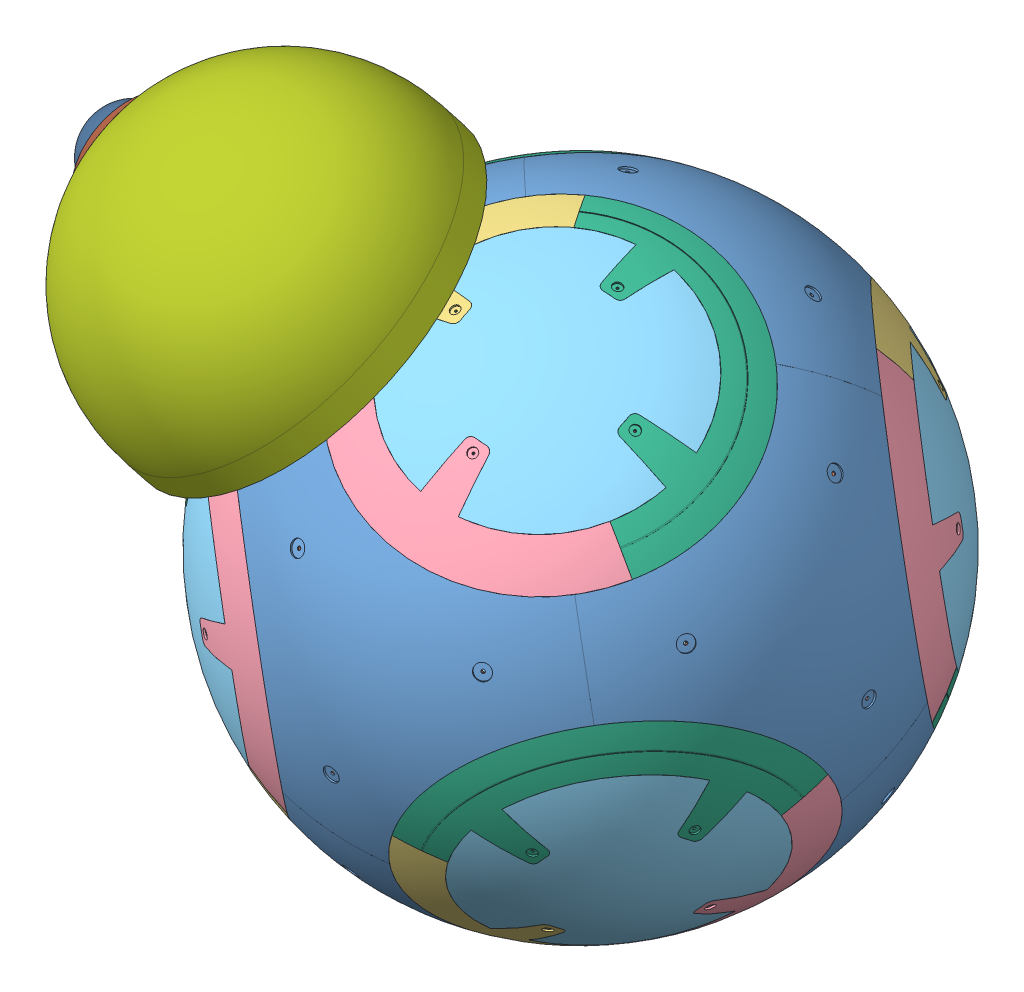
SolidWorks assembly BB-8, configuration Default. Lengths in mm.
Overall size (733.51 768.7 748.54).
63 component instances, 12 part files, 67 mates.
Components (placement in the parent):
- BB-8Shell2-41: BB-8Shell2 [Default] at (-357.0891 -1245.3708 1823.2299) x (-0.707206 0.437014 -0.555769) z (-0.249951 -0.889864 -0.381663) size (215.21 215.21 215.21)
- BB-8Shell2-42: BB-8Shell2 [Default] at (-357.0891 -1245.3708 1823.2299) x (-0.249951 -0.889864 -0.381663) z (-0.661351 -0.131 0.738549) size (215.21 215.21 215.21)
- BB-8Shell2-43: BB-8Shell2 [Default] at (-357.0891 -1245.3708 1823.2299) x (-0.707206 0.437014 -0.555769) z (0.661351 0.131 -0.738549) size (215.21 215.21 215.21)
- BB-8Shell2-44: BB-8Shell2 [Default] at (-357.0891 -1245.3708 1823.2299) x (-0.707206 0.437014 -0.555769) z (-0.661351 -0.131 0.738549) size (215.21 215.21 215.21)
- BB-8Shell2-45: BB-8Shell2 [Default] at (-357.0891 -1245.3708 1823.2299) x (0.661351 0.131 -0.738549) z (-0.707206 0.437014 -0.555769) size (215.21 215.21 215.21)
- BB-8Shell2-46: BB-8Shell2 [Default] at (-357.0891 -1245.3708 1823.2299) x (-0.249951 -0.889864 -0.381663) z (-0.707206 0.437014 -0.555769) size (215.21 215.21 215.21)
- BB-8Shell2-47: BB-8Shell2 [Default] at (-357.0891 -1245.3708 1823.2299) x (0.707206 -0.437014 0.555769) z (0.661351 0.131 -0.738549) size (215.21 215.21 215.21)
- BB-8Shell2-48: BB-8Shell2 [Default] at (-357.0891 -1245.3708 1823.2299) x (0.707206 -0.437014 0.555769) z (0.249951 0.889864 0.381663) size (215.21 215.21 215.21)
- BB-8Shell3-2: BB-8Shell3 [Default] at (-357.0891 -1245.3708 1823.2299) x (-0.644387 -0.72186 0.252356) z (0.707206 -0.437014 0.555769) size (40 18.04 169.3)
- BB-8Shell3-3: BB-8Shell3 [Default] at (-357.0891 -1245.3708 1823.2299) x (0.323328 -0.938244 0.123111) z (-0.661351 -0.131 0.738549) size (40 18.04 169.3)
- BB-8Shell3-4: BB-8Shell3 [Default] at (-357.0891 -1245.3708 1823.2299) x (0.290904 -0.536598 -0.792109) z (-0.707206 0.437014 -0.555769) size (40 18.04 169.3)
- BB-8Shell3-7: BB-8Shell3 [Default] at (-357.0891 -1245.3708 1823.2299) x (-0.967716 0.216385 0.129245) z (0.249951 0.889864 0.381663) size (40 18.04 169.3)
- BB-8Shell3-10: BB-8Shell3 [Default] at (-357.0891 -1245.3708 1823.2299) x (-0.644387 -0.72186 0.252356) z (-0.707206 0.437014 -0.555769) size (40 18.04 169.3)
- BB-8Shell3-11: BB-8Shell3 [Default] at (-357.0891 -1245.3708 1823.2299) x (0.290904 -0.536598 -0.792109) z (0.707206 -0.437014 0.555769) size (40 18.04 169.3)
- BB-8Shell3-13: BB-8Shell3 [Default] at (-357.0891 -1245.3708 1823.2299) x (0.967716 -0.216385 -0.129245) z (0.249951 0.889864 0.381663) size (40 18.04 169.3)
- BB-8Shell3-14: BB-8Shell3 [Default] at (-357.0891 -1245.3708 1823.2299) x (0.323328 -0.938244 0.123111) z (0.661351 0.131 -0.738549) size (40 18.04 169.3)
- BB-8Shell3-15: BB-8Shell3 [Default] at (-357.0891 -1245.3708 1823.2299) x (-0.676812 -0.320213 -0.662864) z (0.661351 0.131 -0.738549) size (40 18.04 169.3)
- BB-8Shell3-16: BB-8Shell3 [Default] at (-357.0891 -1245.3708 1823.2299) x (-0.676812 -0.320213 -0.662864) z (-0.661351 -0.131 0.738549) size (40 18.04 169.3)
- BB-8Shell3-17: BB-8Shell3 [Default] at (-357.0891 -1245.3708 1823.2299) x (0.032424 -0.401646 0.915221) z (-0.249951 -0.889864 -0.381663) size (40 18.04 169.3)
- BB-8Shell3-18: BB-8Shell3 [Default] at (-357.0891 -1245.3708 1823.2299) x (-0.032424 0.401646 -0.915221) z (-0.249951 -0.889864 -0.381663) size (40 18.04 169.3)
- BB-8Panel-1: BB-8Panel [Default] at (-341.2732 -1423.0162 1729.0677) x (0.967716 -0.216385 -0.129245) z (0.032424 -0.401646 0.915221) size (286.79 46.44 286.79)
  - BB-8Shell4-2: BB-8Shell4 [Default] at (-65.915 190.0653 14.3158) size (89.69 38.2 195.88)
  - BB-8Shell5-2: BB-8Shell5 [Default] at (-65.915 190.0653 14.3158) x (0 0 -1) z (1 0 0) size (89.69 38.2 248.37)
  - BB-8Shell6-4: BB-8Shell6 [Default] at (-65.915 190.0653 14.3158) size (217.05 29.8 217.05)
  - BB-8Shell1-2: BB-8Shell1 [Default] at (-65.915 190.0653 14.3158) x (0 0 1) z (-1 0 0) size (215.09 38.2 215.09)
- BB-8Panel-2: BB-8Panel [Default] at (-453.194 -1107.0464 1712.3032) x (0.644387 0.72186 -0.252356) z (0.290904 -0.536598 -0.792109) size (286.79 46.44 286.79)
  - BB-8Shell4-2: BB-8Shell4 [Default] at (-65.915 190.0653 14.3158) size (89.69 38.2 195.88)
  - BB-8Shell5-2: BB-8Shell5 [Default] at (-65.915 190.0653 14.3158) x (0 0 -1) z (1 0 0) size (89.69 38.2 248.37)
  - BB-8Shell6-4: BB-8Shell6 [Default] at (-65.915 190.0653 14.3158) size (217.05 29.8 217.05)
  - BB-8Shell1-2: BB-8Shell1 [Default] at (-65.915 190.0653 14.3158) x (0 0 1) z (-1 0 0) size (215.09 38.2 215.09)
- BB-8Panel-3: BB-8Panel [Default] at (-471.1658 -1336.6978 1962.2278) x (0.323328 -0.938244 0.123111) z (0.676812 0.320213 0.662864) size (286.79 46.44 286.79)
  - BB-8Shell4-2: BB-8Shell4 [Default] at (-65.915 190.0653 14.3158) size (89.69 38.2 195.88)
  - BB-8Shell5-2: BB-8Shell5 [Default] at (-65.915 190.0653 14.3158) x (0 0 -1) z (1 0 0) size (89.69 38.2 248.37)
  - BB-8Shell6-4: BB-8Shell6 [Default] at (-65.915 190.0653 14.3158) size (217.05 29.8 217.05)
  - BB-8Shell1-2: BB-8Shell1 [Default] at (-65.915 190.0653 14.3158) x (0 0 1) z (-1 0 0) size (215.09 38.2 215.09)
- BB-8Panel-4: BB-8Panel [Default] at (-262.3906 -1163.212 1665.2531) x (-0.323328 0.938244 -0.123111) z (0.676812 0.320213 0.662864) size (286.79 46.44 286.79)
  - BB-8Shell4-2: BB-8Shell4 [Default] at (-65.915 190.0653 14.3158) size (89.69 38.2 195.88)
  - BB-8Shell5-2: BB-8Shell5 [Default] at (-65.915 190.0653 14.3158) x (0 0 -1) z (1 0 0) size (89.69 38.2 248.37)
  - BB-8Shell6-4: BB-8Shell6 [Default] at (-65.915 190.0653 14.3158) size (217.05 29.8 217.05)
  - BB-8Shell1-2: BB-8Shell1 [Default] at (-65.915 190.0653 14.3158) x (0 0 1) z (-1 0 0) size (215.09 38.2 215.09)
- BB-8Panel-5: BB-8Panel [Default] at (-232.6238 -1282.7281 1977.4615) x (-0.290904 0.536598 0.792109) z (-0.644387 -0.72186 0.252356) size (286.79 46.44 286.79)
  - BB-8Shell4-2: BB-8Shell4 [Default] at (-65.915 190.0653 14.3158) size (89.69 38.2 195.88)
  - BB-8Shell5-2: BB-8Shell5 [Default] at (-65.915 190.0653 14.3158) x (0 0 -1) z (1 0 0) size (89.69 38.2 248.37)
  - BB-8Shell6-4: BB-8Shell6 [Default] at (-65.915 190.0653 14.3158) size (217.05 29.8 217.05)
  - BB-8Shell1-2: BB-8Shell1 [Default] at (-65.915 190.0653 14.3158) x (0 0 1) z (-1 0 0) size (215.09 38.2 215.09)
- BB-8Panel-6: BB-8Panel [Default] at (-321.2985 -1099.6154 1957.9479) x (0.032424 -0.401646 0.915221) z (0.967716 -0.216385 -0.129245) size (286.79 46.44 286.79)
  - BB-8Shell4-2: BB-8Shell4 [Default] at (-65.915 190.0653 14.3158) size (89.69 38.2 195.88)
  - BB-8Shell5-2: BB-8Shell5 [Default] at (-65.915 190.0653 14.3158) x (0 0 -1) z (1 0 0) size (89.69 38.2 248.37)
  - BB-8Shell6-4: BB-8Shell6 [Default] at (-65.915 190.0653 14.3158) size (217.05 29.8 217.05)
  - BB-8Shell1-2: BB-8Shell1 [Default] at (-65.915 190.0653 14.3158) x (0 0 1) z (-1 0 0) size (215.09 38.2 215.09)
- BB-8Head-2: BB-8Head [Default] at (-128.3404 -1115.1335 2042.4423) x (-0.144081 -0.60353 0.784215) z (-0.887667 -0.271434 -0.371983) size (300 196.37 346.85)
  - BB-8Head-1: BB-8Head [Default] at (-60.3491 175.3135 319.9466) size (300 195.24 308.7)
  - BB-8HeadBottom-1: BB-8HeadBottom [Default] at (-60.3491 -219.631 319.9466) size (200.31 22.07 200.31)
  - Ball Bearing-1: Ball Bearing [Default] at (-17.9227 146.0076 277.5202) size (19 19 19)
  - Ball Bearing-2: Ball Bearing [Default] at (-102.7755 146.0076 362.373) size (19 19 19)
  - Ball Bearing-3: Ball Bearing [Default] at (-102.7755 146.0076 277.5202) size (19 19 19)
  - Ball Bearing-4: Ball Bearing [Default] at (-17.9227 146.0076 362.373) size (19 19 19)
  - BB-8Eye-1: BB-8Eye [Default] at (-60.3491 241.9765 458.4006) x (0 -0.433816 -0.901002) z (0.901002 -0.390869 0.188196) size (39.5 85 85)
  - BB-8EyeCap-1: BB-8EyeCap [Default] at (-60.3491 238.0721 450.2915) x (0 -0.433816 -0.901002) z (0.650455 -0.684351 0.329502) size (11.02 96.2 96.2)
  - Ball-Bearing-Cap-1: Ball-Bearing-Cap [Default] at (-17.9227 146.0076 277.5202) x (0.917432 -0.390978 0.073862) z (-0.006157 0.171661 0.985137) size (24.66 15.93 24.9)
  - Ball-Bearing-Cap-2: Ball-Bearing-Cap [Default] at (-102.7755 146.0076 277.5202) x (0.996884 -0.064375 0.045583) z (-0.034435 0.164736 0.985736) size (24.66 15.93 24.9)
  - Ball-Bearing-Cap-3: Ball-Bearing-Cap [Default] at (-102.7755 146.0076 362.373) x (0.996884 -0.064375 -0.045583) z (0.034435 -0.164736 0.985736) size (24.66 15.93 24.9)
  - Ball-Bearing-Cap-4: Ball-Bearing-Cap [Default] at (-17.9227 146.0076 362.373) x (0.917432 -0.390978 -0.073862) z (0.006157 -0.171661 0.985137) size (24.66 15.93 24.9)
Mates (geometry in assembly coordinates):
- Coincident32: coincident anti-aligned: plane of BB-8Shell2-46 through (-357.0891 -1245.3708 1823.2299) normal (0.661351 0.131 -0.738549); plane of BB-8Shell2-48 through (-357.0891 -1245.3708 1823.2299) normal (-0.661351 -0.131 0.738549)
- Coincident33: coincident aligned: line of BB-8Shell2-46 through (-449.5763 -1022.6724 1779.911) axis (-0.323328 0.938244 -0.123111); line of BB-8Shell2-48 through (-449.5763 -1022.6724 1779.911) axis (-0.323328 0.938244 -0.123111)
- Coincident34: coincident anti-aligned: circle of BB-8Shell2-46; circle of BB-8Shell2-48
- Coincident36: coincident anti-aligned: plane of BB-8Shell2-47 through (-357.0891 -1245.3708 1823.2299) normal (0.249951 0.889864 0.381663); plane of BB-8Shell2-48 through (-357.0891 -1245.3708 1823.2299) normal (-0.249951 -0.889864 -0.381663)
- Coincident40: coincident aligned: line of BB-8Shell2-47 through (-384.3609 -1142.9682 1602.3341) axis (-0.032424 0.401646 -0.915221); line of BB-8Shell2-48 through (-384.3609 -1142.9682 1602.3341) axis (-0.032424 0.401646 -0.915221)
- Coincident41: coincident anti-aligned: circle of BB-8Shell2-47; circle of BB-8Shell2-48
- Coincident42: coincident anti-aligned: plane of BB-8Shell2-45 through (-357.0891 -1245.3708 1823.2299) normal (0.249951 0.889864 0.381663); plane of BB-8Shell2-46 through (-357.0891 -1245.3708 1823.2299) normal (-0.249951 -0.889864 -0.381663)
- Coincident43: coincident aligned: line of BB-8Shell2-45 through (-594.0366 -1184.5005 1836.4848) axis (-0.967716 0.216385 0.129245); line of BB-8Shell2-46 through (-594.0366 -1184.5005 1836.4848) axis (-0.967716 0.216385 0.129245)
- Coincident44: coincident anti-aligned: circle of BB-8Shell2-45; circle of BB-8Shell2-46
- Coincident45: coincident anti-aligned: plane of BB-8Shell2-42 through (-357.0891 -1245.3708 1823.2299) normal (-0.707206 0.437014 -0.555769); plane of BB-8Shell2-46 through (-357.0891 -1245.3708 1823.2299) normal (0.707206 -0.437014 0.555769)
- Coincident46: coincident aligned: line of BB-8Shell2-42 through (-415.2349 -1099.9058 2011.6019) axis (-0.290904 0.536598 0.792109); line of BB-8Shell2-46 through (-415.2349 -1099.9058 2011.6019) axis (-0.290904 0.536598 0.792109)
- Coincident47: coincident anti-aligned: circle of BB-8Shell2-42; circle of BB-8Shell2-46
- Coincident48: coincident anti-aligned: plane of BB-8Shell2-44 through (-357.0891 -1245.3708 1823.2299) normal (-0.707206 0.437014 -0.555769); plane of BB-8Shell2-45 through (-357.0891 -1245.3708 1823.2299) normal (0.707206 -0.437014 0.555769)
- Coincident49: coincident aligned: line of BB-8Shell2-44 through (-520.2552 -1410.9042 1900.693) axis (-0.644387 -0.72186 0.252356); line of BB-8Shell2-45 through (-520.2552 -1410.9042 1900.693) axis (-0.644387 -0.72186 0.252356)
- Coincident50: coincident anti-aligned: circle of BB-8Shell2-44; circle of BB-8Shell2-45
- Coincident51: coincident anti-aligned: plane of BB-8Shell2-41 through (-357.0891 -1245.3708 1823.2299) normal (-0.707206 0.437014 -0.555769); plane of BB-8Shell2-47 through (-357.0891 -1245.3708 1823.2299) normal (0.707206 -0.437014 0.555769)
- Coincident52: coincident aligned: line of BB-8Shell2-41 through (-298.9433 -1390.8358 1634.8579) axis (0.290904 -0.536598 -0.792109); line of BB-8Shell2-47 through (-298.9433 -1390.8358 1634.8579) axis (0.290904 -0.536598 -0.792109)
- Coincident53: coincident anti-aligned: circle of BB-8Shell2-41; circle of BB-8Shell2-47
- Coincident54: coincident anti-aligned: plane of BB-8Shell2-43 through (-357.0891 -1245.3708 1823.2299) normal (-0.707206 0.437014 -0.555769); plane of BB-8Shell2-48 through (-357.0891 -1245.3708 1823.2299) normal (0.707206 -0.437014 0.555769)
- Coincident55: coincident aligned: line of BB-8Shell2-43 through (-193.923 -1079.8374 1745.7668) axis (0.644387 0.72186 -0.252356); line of BB-8Shell2-48 through (-193.923 -1079.8374 1745.7668) axis (0.644387 0.72186 -0.252356)
- Coincident56: coincident anti-aligned: circle of BB-8Shell2-43; circle of BB-8Shell2-48
- Coincident59: coincident aligned: circle of BB-8Shell2-42; circle of BB-8Shell3-7
- Coincident60: coincident anti-aligned: plane of BB-8Shell2-44 through (-357.0891 -1245.3708 1823.2299) normal (0.245967 0.698827 0.67167); plane of BB-8Shell3-7 through (-357.0891 -1245.3708 1823.2299) normal (-0.245967 -0.698827 -0.67167)
- Coincident70: coincident aligned: circle of BB-8Shell2-42; circle of BB-8Shell3-3
- Coincident71: coincident aligned: circle of BB-8Shell2-42; circle of BB-8Shell3-3
- Coincident74: coincident anti-aligned: circle of BB-8Shell2-44; circle of BB-8Shell3-4
- Coincident75: coincident anti-aligned: circle of BB-8Shell2-44; circle of BB-8Shell3-4
- Coincident77: coincident aligned: circle of BB-8Shell2-41; circle of BB-8Shell3-2
- Coincident78: coincident aligned: circle of BB-8Shell2-41; circle of BB-8Shell3-2
- Coincident85: coincident anti-aligned: circle of BB-8Shell2-42; circle of BB-8Shell3-10
- Coincident86: coincident aligned: circle of BB-8Shell2-46; plane of BB-8Shell3-10 through (-357.0891 -1245.3708 1823.2299) normal (-0.565061 0.227131 -0.793169)
- Coincident91: coincident aligned: circle of BB-8Shell2-43; circle of BB-8Shell3-11
- Coincident92: coincident aligned: circle of BB-8Shell2-43; circle of BB-8Shell3-11
- Coincident93: coincident anti-aligned: circle of BB-8Shell2-43; circle of BB-8Shell3-18
- Coincident94: coincident aligned: circle of BB-8Shell2-41; circle of BB-8Shell3-18
- Coincident95: coincident aligned: circle of BB-8Shell2-44; circle of BB-8Shell3-16
- Coincident96: coincident anti-aligned: circle of BB-8Shell2-41; circle of BB-8Shell3-16
- Coincident98: coincident aligned: circle of BB-8Shell2-47; circle of BB-8Shell3-14
- Coincident99: coincident anti-aligned: circle of BB-8Shell2-45; circle of BB-8Shell3-14
- Coincident100: coincident anti-aligned: circle of BB-8Shell2-46; circle of BB-8Shell3-17
- Coincident101: coincident anti-aligned: circle of BB-8Shell2-46; circle of BB-8Shell3-17
- Coincident102: coincident anti-aligned: circle of BB-8Shell2-46; circle of BB-8Shell3-15
- Coincident103: coincident aligned: circle of BB-8Shell2-48; circle of BB-8Shell3-15
- Coincident104: coincident aligned: circle of BB-8Shell2-48; circle of BB-8Shell3-13
- Coincident105: coincident anti-aligned: circle of BB-8Shell2-47; circle of BB-8Shell3-13
- Concentric28: concentric aligned: cylinder of BB-8Shell2-42 through (-357.0891 -1245.3708 1823.2299) axis (0.097953 -0.405206 -0.908963) radius 1.5; cylinder of BB-8Shell3-10 through (-357.0891 -1245.3708 1823.2299) axis (0.097953 -0.405206 -0.908963) radius 1.5
- Coincident107: coincident aligned: cone of BB-8Shell2-43 through (-306.2093 -1064.2307 1900.921) axis (-0.249951 -0.889864 -0.381663); cone of BB-8Panel-1/BB-8Shell4-2 through (-306.2093 -1064.2307 1900.921) axis (-0.249951 -0.889864 -0.381663)
- Coincident108: coincident anti-aligned: plane of BB-8Shell2-43 through (-357.0891 -1245.3708 1823.2299) normal (0.094165 0.369966 -0.924261); plane of BB-8Panel-1/BB-8Shell1-2 through (-357.0891 -1245.3708 1823.2299) normal (-0.094165 -0.369966 0.924261)
- Concentric38: concentric: sphere of BB-8Shell2-41; sphere of BB-8Panel-3/BB-8Shell5-2
- Coincident111: coincident aligned: cone of BB-8Shell2-43 through (-222.465 -1218.7046 1672.8914) axis (-0.661351 -0.131 0.738549); cone of BB-8Panel-3/BB-8Shell5-2 through (-222.465 -1218.7046 1672.8914) axis (-0.661351 -0.131 0.738549)
- Concentric39: concentric: sphere of BB-8Shell2-42; sphere of BB-8Panel-4/BB-8Shell5-2
- Coincident112: coincident aligned: cone of BB-8Shell2-46 through (-491.7132 -1272.037 1973.5684) axis (0.661351 0.131 -0.738549); cone of BB-8Panel-4/BB-8Shell1-2 through (-491.7132 -1272.037 1973.5684) axis (0.661351 0.131 -0.738549)
- Concentric40: concentric: sphere of BB-8Shell2-44; sphere of BB-8Panel-6/BB-8Shell5-2
- Coincident113: coincident aligned: cone of BB-8Shell2-41 through (-407.9689 -1426.5109 1745.5388) axis (0.249951 0.889864 0.381663); cone of BB-8Panel-6/BB-8Shell1-2 through (-407.9689 -1426.5109 1745.5388) axis (0.249951 0.889864 0.381663)
- Tangent10: tangent aligned: sphere of BB-8Panel-5/BB-8Shell1-2; sphere of BB-8Shell2-47
- Coincident114: coincident aligned: cone of BB-8Shell2-48 through (-501.0474 -1156.4125 1710.098) axis (0.707206 -0.437014 0.555769); cone of BB-8Panel-5/BB-8Shell4-2 through (-501.0474 -1156.4125 1710.098) axis (0.707206 -0.437014 0.555769)
- Concentric41: concentric: sphere of BB-8Shell2-41; sphere of BB-8Panel-2/BB-8Shell5-2
- Coincident115: coincident aligned: cone of BB-8Shell2-42 through (-213.1308 -1334.3291 1936.3618) axis (-0.707206 0.437014 -0.555769); cone of BB-8Panel-2/BB-8Shell1-2 through (-213.1308 -1334.3291 1936.3618) axis (-0.707206 0.437014 -0.555769)
- Coincident116: coincident anti-aligned: circle of BB-8Shell2-45; circle of BB-8Panel-6/BB-8Shell1-2
- Coincident117: coincident anti-aligned: circle of BB-8Shell2-45; circle of BB-8Panel-4/BB-8Shell1-2
- Coincident118: coincident anti-aligned: circle of BB-8Shell2-47; circle of BB-8Panel-3/BB-8Shell1-2
- Coincident119: coincident anti-aligned: circle of BB-8Shell2-47; circle of BB-8Panel-5/BB-8Shell4-2
- Coincident120: coincident anti-aligned: circle of BB-8Shell2-44; circle of BB-8Panel-2/BB-8Shell4-2
- Tangent21: tangent anti-aligned: sphere of BB-8Shell2-42; sphere of BB-8Head-2/Ball Bearing-2
- Tangent22: tangent anti-aligned: sphere of BB-8Shell2-46; sphere of BB-8Head-2/Ball Bearing-1
- Tangent23: tangent anti-aligned: sphere of BB-8Shell2-46; sphere of BB-8Head-2/Ball Bearing-4
- Tangent24: tangent anti-aligned: sphere of BB-8Panel-1/BB-8Shell6-4; sphere of BB-8Head-2/Ball Bearing-3
